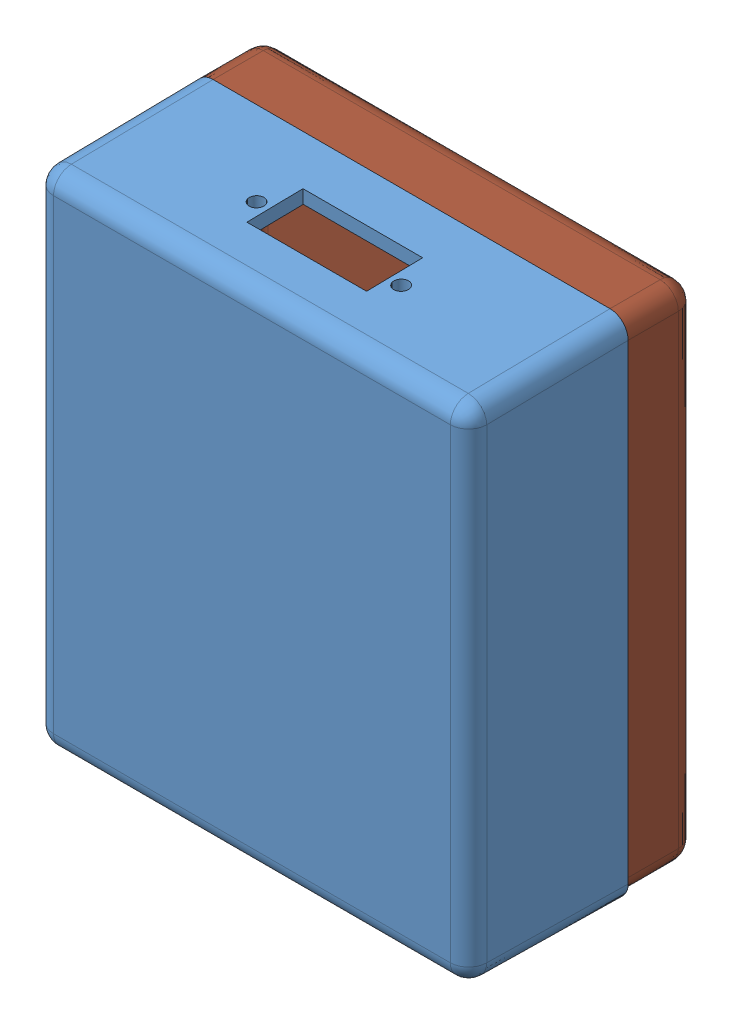
SolidWorks assembly Assem1, configuration Default. Lengths in mm.
Overall size (95 111.22 50).
418 component instances, 30 part files, 6 mates.
Components (placement in the parent):
- below part-1: below part [Default] at (-70.2324 -43.7689 -6.4145) size (95 111.22 37.01)
- Cell_module.step-1: Cell_module.step [Default] at (48.1396 -72.1244 16.2355) x (-1 0 0) z (0 0 -1) size (84.21 76.07 15.13)
  - Board.step-1: Board.step [Default] at origin size (82.17 76.07 0.41)
    - Open CASCADE STEP translator 6.8 1.1.1.step-1: Open CASCADE STEP translator 6.8 1.1.1.step [Default] at (0 0 -0.4115) size (82.17 76.07 0.41)
  - J3.step-1: J3.step [Default] at origin size (11.51 9.91 13)
    - 5828975392.step-1: 5828975392.step [Default] at (116.226 82.501 3.81) x (0 1 0) z (1 0 0) size (9.91 13 11.51)
  - J2.step-1: J2.step [Default] at origin size (11.51 9.91 13)
    - 5828975392.step-1: 5828975392.step [Default] at (116.226 112.989 3.81) x (0 1 0) z (1 0 0) size (9.91 13 11.51)
  - J1.step-1: J1.step [Default] at origin size (11.51 9.91 13)
    - 5828975392.step-1: 5828975392.step [Default] at (116.226 51.895 3.81) x (0 1 0) z (1 0 0) size (9.91 13 11.51)
  - Thermal.step-1: Thermal.step [Default] at origin size (12.18 15.85 12.05)
    - 5828975232.step-1: 5828975232.step [Default] at (118.372 66.6952 0.49) x (0 1 0) z (1 0 0) size (15.85 12.05 12.18)
      - Open CASCADE STEP translator 6.8 1.5.1.1.step-1: Open CASCADE STEP translator 6.8 1.5.1.1.step [Default] at origin size (15.85 12.05 12.18)
      - Open CASCADE STEP translator 6.8 1.5.1.2.step-1: Open CASCADE STEP translator 6.8 1.5.1.2.step [Default] at origin
  - Power.step-1: Power.step [Default] at origin size (12.18 15.85 12.05)
    - 5828975232.step-1: 5828975232.step [Default] at (118.372 97.1832 0.49) x (0 1 0) z (1 0 0) size (15.85 12.05 12.18)
      - Open CASCADE STEP translator 6.8 1.5.1.1.step-1: Open CASCADE STEP translator 6.8 1.5.1.1.step [Default] at origin size (15.85 12.05 12.18)
      - Open CASCADE STEP translator 6.8 1.5.1.2.step-1: Open CASCADE STEP translator 6.8 1.5.1.2.step [Default] at origin
  - U1_U5.step-1: U1_U5.step [Default] at origin size (7 2.7 2)
    - 5828972992.step-1: 5828972992.step [Default] at (52.631 109.3475 0) x (1 0 0) z (0 0 1) size (7 2.7 2)
      - Body.step-1: Body.step [Default] at origin size (4.4 2.7 1.95)
      - PinsArrayLR.step-1: PinsArrayLR.step [Default] at origin size (7 1.67 1.12)
  - U1_U4.step-1: U1_U4.step [Default] at origin size (7 2.7 2)
    - 5828972992.step-1: 5828972992.step [Default] at (52.631 96.9015 0) x (1 0 0) z (0 0 1) size (7 2.7 2)
      - Body.step-1: Body.step [Default] at origin size (4.4 2.7 1.95)
      - PinsArrayLR.step-1: PinsArrayLR.step [Default] at origin size (7 1.67 1.12)
  - U1_U3.step-1: U1_U3.step [Default] at origin size (7 2.7 2)
    - 5828972992.step-1: 5828972992.step [Default] at (52.631 85.0905 0) x (1 0 0) z (0 0 1) size (7 2.7 2)
      - Body.step-1: Body.step [Default] at origin size (4.4 2.7 1.95)
      - PinsArrayLR.step-1: PinsArrayLR.step [Default] at origin size (7 1.67 1.12)
  - U1_U2.step-1: U1_U2.step [Default] at origin size (7 2.7 2)
    - 5828972992.step-1: 5828972992.step [Default] at (52.631 72.9055 0) x (1 0 0) z (0 0 1) size (7 2.7 2)
      - Body.step-1: Body.step [Default] at origin size (4.4 2.7 1.95)
      - PinsArrayLR.step-1: PinsArrayLR.step [Default] at origin size (7 1.67 1.12)
  - U1_U1.step-1: U1_U1.step [Default] at origin size (7 2.7 2)
    - 5828972992.step-1: 5828972992.step [Default] at (52.631 61.3884 0) x (1 0 0) z (0 0 1) size (7 2.7 2)
      - Body.step-1: Body.step [Default] at origin size (4.4 2.7 1.95)
      - PinsArrayLR.step-1: PinsArrayLR.step [Default] at origin size (7 1.67 1.12)
  - Tx.step-1: Tx.step [Default] at origin size (7.4 5.75 10.4)
    - 5828979312.step-1: 5828979312.step [Default] at (74.1355 115.951 0) x (-1 0 0) z (0 1 0) size (7.4 10.4 5.75)
  - Rx.step-1: Rx.step [Default] at origin size (7.4 5.75 10.4)
    - 5828972752.step-1: 5828972752.step [Default] at (73.259 48.658 0) x (1 0 0) z (0 -1 0) size (7.4 10.4 5.75)
  - R28_U5.step-1: R28_U5.step [Default] at origin size (5 2.55 1.07)
    - Res_Yageo_RC2010JK-071KL_eec.step-1: Res_Yageo_RC2010JK-071KL_eec.step [Default] at (82.99 109.347 0) x (-1 0 0) z (0 0 1) size (5 2.55 1.07)
      - RC2010JK-071KL.step-1: RC2010JK-071KL.step [Default] x (1 0 0) z (0 -1 0) size (5 0.65 2.5)
      - Yageo.step-1: Yageo.step [Default] at (0.1744 -0.7742 0.648) size (1.81 0.83 0.83)
  - R28_U4.step-1: R28_U4.step [Default] at origin size (5 2.55 1.07)
    - Res_Yageo_RC2010JK-071KL_eec.step-1: Res_Yageo_RC2010JK-071KL_eec.step [Default] at (82.99 95.504 0) x (-1 0 0) z (0 0 1) size (5 2.55 1.07)
      - RC2010JK-071KL.step-1: RC2010JK-071KL.step [Default] x (1 0 0) z (0 -1 0) size (5 0.65 2.5)
      - Yageo.step-1: Yageo.step [Default] at (0.1744 -0.7742 0.648) size (1.81 0.83 0.83)
  - R28_U3.step-1: R28_U3.step [Default] at origin size (5 2.55 1.07)
    - Res_Yageo_RC2010JK-071KL_eec.step-1: Res_Yageo_RC2010JK-071KL_eec.step [Default] at (82.99 80.391 0) x (-1 0 0) z (0 0 1) size (5 2.55 1.07)
      - RC2010JK-071KL.step-1: RC2010JK-071KL.step [Default] x (1 0 0) z (0 -1 0) size (5 0.65 2.5)
      - Yageo.step-1: Yageo.step [Default] at (0.1744 -0.7742 0.648) size (1.81 0.83 0.83)
  - R28_U2.step-1: R28_U2.step [Default] at origin size (5 2.55 1.07)
    - Res_Yageo_RC2010JK-071KL_eec.step-1: Res_Yageo_RC2010JK-071KL_eec.step [Default] at (82.99 64.643 0) x (-1 0 0) z (0 0 1) size (5 2.55 1.07)
      - RC2010JK-071KL.step-1: RC2010JK-071KL.step [Default] x (1 0 0) z (0 -1 0) size (5 0.65 2.5)
      - Yageo.step-1: Yageo.step [Default] at (0.1744 -0.7742 0.648) size (1.81 0.83 0.83)
  - R28_U1.step-1: R28_U1.step [Default] at origin size (5 2.55 1.07)
    - Res_Yageo_RC2010JK-071KL_eec.step-1: Res_Yageo_RC2010JK-071KL_eec.step [Default] at (82.99 49.911 0) x (-1 0 0) z (0 0 1) size (5 2.55 1.07)
      - RC2010JK-071KL.step-1: RC2010JK-071KL.step [Default] x (1 0 0) z (0 -1 0) size (5 0.65 2.5)
      - Yageo.step-1: Yageo.step [Default] at (0.1744 -0.7742 0.648) size (1.81 0.83 0.83)
  - R27_U5.step-1: R27_U5.step [Default] at origin size (5 2.55 1.07)
    - Res_Yageo_RC2010JK-071KL_eec.step-1: Res_Yageo_RC2010JK-071KL_eec.step [Default] at (89.535 106.4728 0) x (-1 0 0) z (0 0 1) size (5 2.55 1.07)
      - RC2010JK-071KL.step-1: RC2010JK-071KL.step [Default] x (1 0 0) z (0 -1 0) size (5 0.65 2.5)
      - Yageo.step-1: Yageo.step [Default] at (0.1744 -0.7742 0.648) size (1.81 0.83 0.83)
  - R27_U4.step-1: R27_U4.step [Default] at origin size (5 2.55 1.07)
    - Res_Yageo_RC2010JK-071KL_eec.step-1: Res_Yageo_RC2010JK-071KL_eec.step [Default] at (89.535 92.1418 0) x (-1 0 0) z (0 0 1) size (5 2.55 1.07)
      - RC2010JK-071KL.step-1: RC2010JK-071KL.step [Default] x (1 0 0) z (0 -1 0) size (5 0.65 2.5)
      - Yageo.step-1: Yageo.step [Default] at (0.1744 -0.7742 0.648) size (1.81 0.83 0.83)
  - R27_U3.step-1: R27_U3.step [Default] at origin size (5 2.55 1.07)
    - Res_Yageo_RC2010JK-071KL_eec.step-1: Res_Yageo_RC2010JK-071KL_eec.step [Default] at (89.535 77.8109 0) x (-1 0 0) z (0 0 1) size (5 2.55 1.07)
      - RC2010JK-071KL.step-1: RC2010JK-071KL.step [Default] x (1 0 0) z (0 -1 0) size (5 0.65 2.5)
      - Yageo.step-1: Yageo.step [Default] at (0.1744 -0.7742 0.648) size (1.81 0.83 0.83)
  - R27_U2.step-1: R27_U2.step [Default] at origin size (5 2.55 1.07)
    - Res_Yageo_RC2010JK-071KL_eec.step-1: Res_Yageo_RC2010JK-071KL_eec.step [Default] at (89.535 63.4799 0) x (-1 0 0) z (0 0 1) size (5 2.55 1.07)
      - RC2010JK-071KL.step-1: RC2010JK-071KL.step [Default] x (1 0 0) z (0 -1 0) size (5 0.65 2.5)
      - Yageo.step-1: Yageo.step [Default] at (0.1744 -0.7742 0.648) size (1.81 0.83 0.83)
  - R27_U1.step-1: R27_U1.step [Default] at origin size (5 2.55 1.07)
    - Res_Yageo_RC2010JK-071KL_eec.step-1: Res_Yageo_RC2010JK-071KL_eec.step [Default] at (89.535 49.149 0) x (-1 0 0) z (0 0 1) size (5 2.55 1.07)
      - RC2010JK-071KL.step-1: RC2010JK-071KL.step [Default] x (1 0 0) z (0 -1 0) size (5 0.65 2.5)
      - Yageo.step-1: Yageo.step [Default] at (0.1744 -0.7742 0.648) size (1.81 0.83 0.83)
  - R26_U5.step-1: R26_U5.step [Default] at origin size (5 2.55 1.07)
    - Res_Yageo_RC2010JK-071KL_eec.step-1: Res_Yageo_RC2010JK-071KL_eec.step [Default] at (82.99 113.03 0) size (5 2.55 1.07)
      - RC2010JK-071KL.step-1: RC2010JK-071KL.step [Default] x (1 0 0) z (0 -1 0) size (5 0.65 2.5)
      - Yageo.step-1: Yageo.step [Default] at (0.1744 -0.7742 0.648) size (1.81 0.83 0.83)
  - R26_U4.step-1: R26_U4.step [Default] at origin size (5 2.55 1.07)
    - Res_Yageo_RC2010JK-071KL_eec.step-1: Res_Yageo_RC2010JK-071KL_eec.step [Default] at (82.99 99.5045 0) size (5 2.55 1.07)
      - RC2010JK-071KL.step-1: RC2010JK-071KL.step [Default] x (1 0 0) z (0 -1 0) size (5 0.65 2.5)
      - Yageo.step-1: Yageo.step [Default] at (0.1744 -0.7742 0.648) size (1.81 0.83 0.83)
  - R26_U3.step-1: R26_U3.step [Default] at origin size (5 2.55 1.07)
    - Res_Yageo_RC2010JK-071KL_eec.step-1: Res_Yageo_RC2010JK-071KL_eec.step [Default] at (82.99 84.582 0) size (5 2.55 1.07)
      - RC2010JK-071KL.step-1: RC2010JK-071KL.step [Default] x (1 0 0) z (0 -1 0) size (5 0.65 2.5)
      - Yageo.step-1: Yageo.step [Default] at (0.1744 -0.7742 0.648) size (1.81 0.83 0.83)
  - R26_U2.step-1: R26_U2.step [Default] at origin size (5 2.55 1.07)
    - Res_Yageo_RC2010JK-071KL_eec.step-1: Res_Yageo_RC2010JK-071KL_eec.step [Default] at (82.99 68.961 0) size (5 2.55 1.07)
      - RC2010JK-071KL.step-1: RC2010JK-071KL.step [Default] x (1 0 0) z (0 -1 0) size (5 0.65 2.5)
      - Yageo.step-1: Yageo.step [Default] at (0.1744 -0.7742 0.648) size (1.81 0.83 0.83)
  - R26_U1.step-1: R26_U1.step [Default] at origin size (5 2.55 1.07)
    - Res_Yageo_RC2010JK-071KL_eec.step-1: Res_Yageo_RC2010JK-071KL_eec.step [Default] at (83.058 54.102 0) size (5 2.55 1.07)
      - RC2010JK-071KL.step-1: RC2010JK-071KL.step [Default] x (1 0 0) z (0 -1 0) size (5 0.65 2.5)
      - Yageo.step-1: Yageo.step [Default] at (0.1744 -0.7742 0.648) size (1.81 0.83 0.83)
  - R25_U5.step-1: R25_U5.step [Default] at origin size (5 2.55 1.07)
    - Res_Yageo_RC2010JK-071KL_eec.step-1: Res_Yageo_RC2010JK-071KL_eec.step [Default] at (89.535 110.0555 0) size (5 2.55 1.07)
      - RC2010JK-071KL.step-1: RC2010JK-071KL.step [Default] x (1 0 0) z (0 -1 0) size (5 0.65 2.5)
      - Yageo.step-1: Yageo.step [Default] at (0.1744 -0.7742 0.648) size (1.81 0.83 0.83)
  - R25_U4.step-1: R25_U4.step [Default] at origin size (5 2.55 1.07)
    - Res_Yageo_RC2010JK-071KL_eec.step-1: Res_Yageo_RC2010JK-071KL_eec.step [Default] at (89.535 95.7246 0) size (5 2.55 1.07)
      - RC2010JK-071KL.step-1: RC2010JK-071KL.step [Default] x (1 0 0) z (0 -1 0) size (5 0.65 2.5)
      - Yageo.step-1: Yageo.step [Default] at (0.1744 -0.7742 0.648) size (1.81 0.83 0.83)
  - R25_U3.step-1: R25_U3.step [Default] at origin size (5 2.55 1.07)
    - Res_Yageo_RC2010JK-071KL_eec.step-1: Res_Yageo_RC2010JK-071KL_eec.step [Default] at (89.535 81.3936 0) size (5 2.55 1.07)
      - RC2010JK-071KL.step-1: RC2010JK-071KL.step [Default] x (1 0 0) z (0 -1 0) size (5 0.65 2.5)
      - Yageo.step-1: Yageo.step [Default] at (0.1744 -0.7742 0.648) size (1.81 0.83 0.83)
  - R25_U2.step-1: R25_U2.step [Default] at origin size (5 2.55 1.07)
    - Res_Yageo_RC2010JK-071KL_eec.step-1: Res_Yageo_RC2010JK-071KL_eec.step [Default] at (89.535 67.0627 0) size (5 2.55 1.07)
      - RC2010JK-071KL.step-1: RC2010JK-071KL.step [Default] x (1 0 0) z (0 -1 0) size (5 0.65 2.5)
      - Yageo.step-1: Yageo.step [Default] at (0.1744 -0.7742 0.648) size (1.81 0.83 0.83)
  - R25_U1.step-1: R25_U1.step [Default] at origin size (5 2.55 1.07)
    - Res_Yageo_RC2010JK-071KL_eec.step-1: Res_Yageo_RC2010JK-071KL_eec.step [Default] at (89.535 52.7317 0) size (5 2.55 1.07)
      - RC2010JK-071KL.step-1: RC2010JK-071KL.step [Default] x (1 0 0) z (0 -1 0) size (5 0.65 2.5)
      - Yageo.step-1: Yageo.step [Default] at (0.1744 -0.7742 0.648) size (1.81 0.83 0.83)
  - R24_U5.step-1: R24_U5.step [Default] at origin size (5 2.55 1.07)
    - Res_Yageo_RC2010JK-071KL_eec.step-1: Res_Yageo_RC2010JK-071KL_eec.step [Default] at (82.99 116.713 0) x (-1 0 0) z (0 0 1) size (5 2.55 1.07)
      - RC2010JK-071KL.step-1: RC2010JK-071KL.step [Default] x (1 0 0) z (0 -1 0) size (5 0.65 2.5)
      - Yageo.step-1: Yageo.step [Default] at (0.1744 -0.7742 0.648) size (1.81 0.83 0.83)
  - R24_U4.step-1: R24_U4.step [Default] at origin size (5 2.55 1.07)
    - Res_Yageo_RC2010JK-071KL_eec.step-1: Res_Yageo_RC2010JK-071KL_eec.step [Default] at (82.99 103.505 0) x (-1 0 0) z (0 0 1) size (5 2.55 1.07)
      - RC2010JK-071KL.step-1: RC2010JK-071KL.step [Default] x (1 0 0) z (0 -1 0) size (5 0.65 2.5)
      - Yageo.step-1: Yageo.step [Default] at (0.1744 -0.7742 0.648) size (1.81 0.83 0.83)
  - R24_U3.step-1: R24_U3.step [Default] at origin size (5 2.55 1.07)
    - Res_Yageo_RC2010JK-071KL_eec.step-1: Res_Yageo_RC2010JK-071KL_eec.step [Default] at (82.99 88.773 0) x (-1 0 0) z (0 0 1) size (5 2.55 1.07)
      - RC2010JK-071KL.step-1: RC2010JK-071KL.step [Default] x (1 0 0) z (0 -1 0) size (5 0.65 2.5)
      - Yageo.step-1: Yageo.step [Default] at (0.1744 -0.7742 0.648) size (1.81 0.83 0.83)
  - R24_U2.step-1: R24_U2.step [Default] at origin size (5 2.55 1.07)
    - Res_Yageo_RC2010JK-071KL_eec.step-1: Res_Yageo_RC2010JK-071KL_eec.step [Default] at (82.99 73.279 0) x (-1 0 0) z (0 0 1) size (5 2.55 1.07)
      - RC2010JK-071KL.step-1: RC2010JK-071KL.step [Default] x (1 0 0) z (0 -1 0) size (5 0.65 2.5)
      - Yageo.step-1: Yageo.step [Default] at (0.1744 -0.7742 0.648) size (1.81 0.83 0.83)
  - R24_U1.step-1: R24_U1.step [Default] at origin size (5 2.55 1.07)
    - Res_Yageo_RC2010JK-071KL_eec.step-1: Res_Yageo_RC2010JK-071KL_eec.step [Default] at (82.99 58.547 0) x (-1 0 0) z (0 0 1) size (5 2.55 1.07)
      - RC2010JK-071KL.step-1: RC2010JK-071KL.step [Default] x (1 0 0) z (0 -1 0) size (5 0.65 2.5)
      - Yageo.step-1: Yageo.step [Default] at (0.1744 -0.7742 0.648) size (1.81 0.83 0.83)
  - R22_U5.step-1: R22_U5.step [Default] at origin size (5 2.55 1.07)
    - Res_Yageo_RC2010JK-071KL_eec.step-1: Res_Yageo_RC2010JK-071KL_eec.step [Default] at (89.535 117.221 0) x (-1 0 0) z (0 0 1) size (5 2.55 1.07)
      - RC2010JK-071KL.step-1: RC2010JK-071KL.step [Default] x (1 0 0) z (0 -1 0) size (5 0.65 2.5)
      - Yageo.step-1: Yageo.step [Default] at (0.1744 -0.7742 0.648) size (1.81 0.83 0.83)
  - R22_U4.step-1: R22_U4.step [Default] at origin size (5 2.55 1.07)
    - Res_Yageo_RC2010JK-071KL_eec.step-1: Res_Yageo_RC2010JK-071KL_eec.step [Default] at (89.535 102.743 0) x (-1 0 0) z (0 0 1) size (5 2.55 1.07)
      - RC2010JK-071KL.step-1: RC2010JK-071KL.step [Default] x (1 0 0) z (0 -1 0) size (5 0.65 2.5)
      - Yageo.step-1: Yageo.step [Default] at (0.1744 -0.7742 0.648) size (1.81 0.83 0.83)
  - R22_U3.step-1: R22_U3.step [Default] at origin size (5 2.55 1.07)
    - Res_Yageo_RC2010JK-071KL_eec.step-1: Res_Yageo_RC2010JK-071KL_eec.step [Default] at (89.535 88.5591 0) x (-1 0 0) z (0 0 1) size (5 2.55 1.07)
      - RC2010JK-071KL.step-1: RC2010JK-071KL.step [Default] x (1 0 0) z (0 -1 0) size (5 0.65 2.5)
      - Yageo.step-1: Yageo.step [Default] at (0.1744 -0.7742 0.648) size (1.81 0.83 0.83)
  - R22_U2.step-1: R22_U2.step [Default] at origin size (5 2.55 1.07)
    - Res_Yageo_RC2010JK-071KL_eec.step-1: Res_Yageo_RC2010JK-071KL_eec.step [Default] at (89.535 74.2281 0) x (-1 0 0) z (0 0 1) size (5 2.55 1.07)
      - RC2010JK-071KL.step-1: RC2010JK-071KL.step [Default] x (1 0 0) z (0 -1 0) size (5 0.65 2.5)
      - Yageo.step-1: Yageo.step [Default] at (0.1744 -0.7742 0.648) size (1.81 0.83 0.83)
  - R22_U1.step-1: R22_U1.step [Default] at origin size (5 2.55 1.07)
    - Res_Yageo_RC2010JK-071KL_eec.step-1: Res_Yageo_RC2010JK-071KL_eec.step [Default] at (89.535 59.8972 0) x (-1 0 0) z (0 0 1) size (5 2.55 1.07)
      - RC2010JK-071KL.step-1: RC2010JK-071KL.step [Default] x (1 0 0) z (0 -1 0) size (5 0.65 2.5)
      - Yageo.step-1: Yageo.step [Default] at (0.1744 -0.7742 0.648) size (1.81 0.83 0.83)
  - R19_U5.step-1: R19_U5.step [Default] at origin size (4.4 2.7 2.01)
    - 5828980992.step-1: 5828980992.step [Default] at (89.408 113.538 0) x (-1 0 0) z (0 0 1) size (4.4 2.7 2.01)
      - term1.step-1: term1.step [Default] at (-1 -0.625 0) size (0.2 1.25 0.95)
      - term2.step-1: term2.step [Default] at (0.8 -0.625 0) size (0.2 1.25 0.95)
      - Body.step-1: Body.step [Default] at (-0.8 -0.6125 0.0095) size (4.4 2.7 1.95)
  - R19_U4.step-1: R19_U4.step [Default] at origin size (4.4 2.7 2.01)
    - 5828980992.step-1: 5828980992.step [Default] at (89.408 99.187 0) x (-1 0 0) z (0 0 1) size (4.4 2.7 2.01)
      - term1.step-1: term1.step [Default] at (-1 -0.625 0) size (0.2 1.25 0.95)
      - term2.step-1: term2.step [Default] at (0.8 -0.625 0) size (0.2 1.25 0.95)
      - Body.step-1: Body.step [Default] at (-0.8 -0.6125 0.0095) size (4.4 2.7 1.95)
  - R19_U3.step-1: R19_U3.step [Default] at origin size (4.4 2.7 2.01)
    - 5828980992.step-1: 5828980992.step [Default] at (89.408 84.836 0) x (-1 0 0) z (0 0 1) size (4.4 2.7 2.01)
      - term1.step-1: term1.step [Default] at (-1 -0.625 0) size (0.2 1.25 0.95)
      - term2.step-1: term2.step [Default] at (0.8 -0.625 0) size (0.2 1.25 0.95)
      - Body.step-1: Body.step [Default] at (-0.8 -0.6125 0.0095) size (4.4 2.7 1.95)
  - R19_U2.step-1: R19_U2.step [Default] at origin size (4.4 2.7 2.01)
    - 5828980992.step-1: 5828980992.step [Default] at (89.408 70.485 0) x (-1 0 0) z (0 0 1) size (4.4 2.7 2.01)
      - term1.step-1: term1.step [Default] at (-1 -0.625 0) size (0.2 1.25 0.95)
      - term2.step-1: term2.step [Default] at (0.8 -0.625 0) size (0.2 1.25 0.95)
      - Body.step-1: Body.step [Default] at (-0.8 -0.6125 0.0095) size (4.4 2.7 1.95)
  - R19_U1.step-1: R19_U1.step [Default] at origin size (4.4 2.7 2.01)
    - 5828980992.step-1: 5828980992.step [Default] at (89.408 56.134 0) x (-1 0 0) z (0 0 1) size (4.4 2.7 2.01)
      - term1.step-1: term1.step [Default] at (-1 -0.625 0) size (0.2 1.25 0.95)
      - term2.step-1: term2.step [Default] at (0.8 -0.625 0) size (0.2 1.25 0.95)
      - Body.step-1: Body.step [Default] at (-0.8 -0.6125 0.0095) size (4.4 2.7 1.95)
  - R18_U5.step-1: R18_U5.step [Default] at origin size (2 1.28 0.65)
    - 5828976432.step-1: 5828976432.step [Default] at (46.1639 106.6602 0) x (-1 0 0) z (0 0 1) size (2 1.28 0.65)
      - term1-0.step-1: term1-0.step [Default] at (-1 -0.6375 0) size (0.4 1.28 0.65)
      - term2-1.step-1: term2-1.step [Default] at (0.6 -0.6375 0) size (0.4 1.28 0.65)
      - body-2.step-1: body-2.step [Default] at (-0.6 -0.6248 0.0065) size (1.2 1.25 0.64)
  - R18_U4.step-1: R18_U4.step [Default] at origin size (2 1.28 0.65)
    - 5828976432.step-1: 5828976432.step [Default] at (46.1639 94.2777 0) x (-1 0 0) z (0 0 1) size (2 1.28 0.65)
      - term1-0.step-1: term1-0.step [Default] at (-1 -0.6375 0) size (0.4 1.28 0.65)
      - term2-1.step-1: term2-1.step [Default] at (0.6 -0.6375 0) size (0.4 1.28 0.65)
      - body-2.step-1: body-2.step [Default] at (-0.6 -0.6248 0.0065) size (1.2 1.25 0.64)
  - R18_U3.step-1: R18_U3.step [Default] at origin size (2 1.28 0.65)
    - 5828976432.step-1: 5828976432.step [Default] at (46.101 82.296 0) x (-1 0 0) z (0 0 1) size (2 1.28 0.65)
      - term1-0.step-1: term1-0.step [Default] at (-1 -0.6375 0) size (0.4 1.28 0.65)
      - term2-1.step-1: term2-1.step [Default] at (0.6 -0.6375 0) size (0.4 1.28 0.65)
      - body-2.step-1: body-2.step [Default] at (-0.6 -0.6248 0.0065) size (1.2 1.25 0.64)
  - R18_U2.step-1: R18_U2.step [Default] at origin size (2 1.28 0.65)
    - 5828976432.step-1: 5828976432.step [Default] at (46.101 70.485 0) x (-1 0 0) z (0 0 1) size (2 1.28 0.65)
      - term1-0.step-1: term1-0.step [Default] at (-1 -0.6375 0) size (0.4 1.28 0.65)
      - term2-1.step-1: term2-1.step [Default] at (0.6 -0.6375 0) size (0.4 1.28 0.65)
      - body-2.step-1: body-2.step [Default] at (-0.6 -0.6248 0.0065) size (1.2 1.25 0.64)
  - R18_U1.step-1: R18_U1.step [Default] at origin size (2 1.28 0.65)
    - 5828976432.step-1: 5828976432.step [Default] at (46.202 58.42 0) x (-1 0 0) z (0 0 1) size (2 1.28 0.65)
      - term1-0.step-1: term1-0.step [Default] at (-1 -0.6375 0) size (0.4 1.28 0.65)
      - term2-1.step-1: term2-1.step [Default] at (0.6 -0.6375 0) size (0.4 1.28 0.65)
      - body-2.step-1: body-2.step [Default] at (-0.6 -0.6248 0.0065) size (1.2 1.25 0.64)
  - R17_U5.step-1: R17_U5.step [Default] at origin size (2 1.28 0.65)
    - 5828976432.step-1: 5828976432.step [Default] at (68.5048 105.029 0) x (-1 0 0) z (0 0 1) size (2 1.28 0.65)
      - term1-0.step-1: term1-0.step [Default] at (-1 -0.6375 0) size (0.4 1.28 0.65)
      - term2-1.step-1: term2-1.step [Default] at (0.6 -0.6375 0) size (0.4 1.28 0.65)
      - body-2.step-1: body-2.step [Default] at (-0.6 -0.6248 0.0065) size (1.2 1.25 0.64)
  - R17_U4.step-1: R17_U4.step [Default] at origin size (2 1.28 0.65)
    - 5828976432.step-1: 5828976432.step [Default] at (68.5048 92.456 0) x (-1 0 0) z (0 0 1) size (2 1.28 0.65)
      - term1-0.step-1: term1-0.step [Default] at (-1 -0.6375 0) size (0.4 1.28 0.65)
      - term2-1.step-1: term2-1.step [Default] at (0.6 -0.6375 0) size (0.4 1.28 0.65)
      - body-2.step-1: body-2.step [Default] at (-0.6 -0.6248 0.0065) size (1.2 1.25 0.64)
  - R17_U3.step-1: R17_U3.step [Default] at origin size (2 1.28 0.65)
    - 5828976432.step-1: 5828976432.step [Default] at (68.5048 80.518 0) x (-1 0 0) z (0 0 1) size (2 1.28 0.65)
      - term1-0.step-1: term1-0.step [Default] at (-1 -0.6375 0) size (0.4 1.28 0.65)
      - term2-1.step-1: term2-1.step [Default] at (0.6 -0.6375 0) size (0.4 1.28 0.65)
      - body-2.step-1: body-2.step [Default] at (-0.6 -0.6248 0.0065) size (1.2 1.25 0.64)
  - R17_U2.step-1: R17_U2.step [Default] at origin size (2 1.28 0.65)
    - 5828976432.step-1: 5828976432.step [Default] at (68.5048 68.707 0) x (-1 0 0) z (0 0 1) size (2 1.28 0.65)
      - term1-0.step-1: term1-0.step [Default] at (-1 -0.6375 0) size (0.4 1.28 0.65)
      - term2-1.step-1: term2-1.step [Default] at (0.6 -0.6375 0) size (0.4 1.28 0.65)
      - body-2.step-1: body-2.step [Default] at (-0.6 -0.6248 0.0065) size (1.2 1.25 0.64)
  - R17_U1.step-1: R17_U1.step [Default] at origin size (2 1.28 0.65)
    - 5828976432.step-1: 5828976432.step [Default] at (68.5048 57.023 0) x (-1 0 0) z (0 0 1) size (2 1.28 0.65)
      - term1-0.step-1: term1-0.step [Default] at (-1 -0.6375 0) size (0.4 1.28 0.65)
      - term2-1.step-1: term2-1.step [Default] at (0.6 -0.6375 0) size (0.4 1.28 0.65)
      - body-2.step-1: body-2.step [Default] at (-0.6 -0.6248 0.0065) size (1.2 1.25 0.64)
  - R16_U5.step-1: R16_U5.step [Default] at origin size (2 1.28 0.65)
    - 5828979792.step-1: 5828979792.step [Default] at (41.4449 104.4568 0) x (1 0 0) z (0 0 1) size (2 1.28 0.65)
      - term1-3.step-1: term1-3.step [Default] at (-1 -0.6375 0) size (0.4 1.28 0.65)
      - term2-4.step-1: term2-4.step [Default] at (0.6 -0.6375 0) size (0.4 1.28 0.65)
      - body-5.step-1: body-5.step [Default] at (-0.6 -0.6248 0.0065) size (1.2 1.25 0.64)
  - R16_U4.step-1: R16_U4.step [Default] at origin size (2 1.28 0.65)
    - 5828979792.step-1: 5828979792.step [Default] at (41.4449 92.0955 0) x (1 0 0) z (0 0 1) size (2 1.28 0.65)
      - term1-3.step-1: term1-3.step [Default] at (-1 -0.6375 0) size (0.4 1.28 0.65)
      - term2-4.step-1: term2-4.step [Default] at (0.6 -0.6375 0) size (0.4 1.28 0.65)
      - body-5.step-1: body-5.step [Default] at (-0.6 -0.6248 0.0065) size (1.2 1.25 0.64)
  - R16_U3.step-1: R16_U3.step [Default] at origin size (2 1.28 0.65)
    - 5828979792.step-1: 5828979792.step [Default] at (41.4449 79.9458 0) x (1 0 0) z (0 0 1) size (2 1.28 0.65)
      - term1-3.step-1: term1-3.step [Default] at (-1 -0.6375 0) size (0.4 1.28 0.65)
      - term2-4.step-1: term2-4.step [Default] at (0.6 -0.6375 0) size (0.4 1.28 0.65)
      - body-5.step-1: body-5.step [Default] at (-0.6 -0.6248 0.0065) size (1.2 1.25 0.64)
  - R16_U2.step-1: R16_U2.step [Default] at origin size (2 1.28 0.65)
    - 5828979792.step-1: 5828979792.step [Default] at (41.4449 67.9255 0) x (1 0 0) z (0 0 1) size (2 1.28 0.65)
      - term1-3.step-1: term1-3.step [Default] at (-1 -0.6375 0) size (0.4 1.28 0.65)
      - term2-4.step-1: term2-4.step [Default] at (0.6 -0.6375 0) size (0.4 1.28 0.65)
      - body-5.step-1: body-5.step [Default] at (-0.6 -0.6248 0.0065) size (1.2 1.25 0.64)
  - R16_U1.step-1: R16_U1.step [Default] at origin size (2 1.28 0.65)
    - 5828979792.step-1: 5828979792.step [Default] at (41.4449 56.0432 0) x (1 0 0) z (0 0 1) size (2 1.28 0.65)
      - term1-3.step-1: term1-3.step [Default] at (-1 -0.6375 0) size (0.4 1.28 0.65)
      - term2-4.step-1: term2-4.step [Default] at (0.6 -0.6375 0) size (0.4 1.28 0.65)
      - body-5.step-1: body-5.step [Default] at (-0.6 -0.6248 0.0065) size (1.2 1.25 0.64)
  - R10_U5.step-1: R10_U5.step [Default] at origin size (5 2.55 1.07)
    - Res_Yageo_RC2010JK-071KL_eec.step-1: Res_Yageo_RC2010JK-071KL_eec.step [Default] at (96.012 109.347 0) x (-1 0 0) z (0 0 1) size (5 2.55 1.07)
      - RC2010JK-071KL.step-1: RC2010JK-071KL.step [Default] x (1 0 0) z (0 -1 0) size (5 0.65 2.5)
      - Yageo.step-1: Yageo.step [Default] at (0.1744 -0.7742 0.648) size (1.81 0.83 0.83)
  - R10_U4.step-1: R10_U4.step [Default] at origin size (5 2.55 1.07)
    - Res_Yageo_RC2010JK-071KL_eec.step-1: Res_Yageo_RC2010JK-071KL_eec.step [Default] at (96.012 95.504 0) x (-1 0 0) z (0 0 1) size (5 2.55 1.07)
      - RC2010JK-071KL.step-1: RC2010JK-071KL.step [Default] x (1 0 0) z (0 -1 0) size (5 0.65 2.5)
      - Yageo.step-1: Yageo.step [Default] at (0.1744 -0.7742 0.648) size (1.81 0.83 0.83)
  - R10_U3.step-1: R10_U3.step [Default] at origin size (5 2.55 1.07)
    - Res_Yageo_RC2010JK-071KL_eec.step-1: Res_Yageo_RC2010JK-071KL_eec.step [Default] at (96.012 80.391 0) x (-1 0 0) z (0 0 1) size (5 2.55 1.07)
      - RC2010JK-071KL.step-1: RC2010JK-071KL.step [Default] x (1 0 0) z (0 -1 0) size (5 0.65 2.5)
      - Yageo.step-1: Yageo.step [Default] at (0.1744 -0.7742 0.648) size (1.81 0.83 0.83)
  - R10_U2.step-1: R10_U2.step [Default] at origin size (5 2.55 1.07)
    - Res_Yageo_RC2010JK-071KL_eec.step-1: Res_Yageo_RC2010JK-071KL_eec.step [Default] at (96.012 64.643 0) x (-1 0 0) z (0 0 1) size (5 2.55 1.07)
      - RC2010JK-071KL.step-1: RC2010JK-071KL.step [Default] x (1 0 0) z (0 -1 0) size (5 0.65 2.5)
      - Yageo.step-1: Yageo.step [Default] at (0.1744 -0.7742 0.648) size (1.81 0.83 0.83)
  - R10_U1.step-1: R10_U1.step [Default] at origin size (5 2.55 1.07)
    - Res_Yageo_RC2010JK-071KL_eec.step-1: Res_Yageo_RC2010JK-071KL_eec.step [Default] at (96.012 49.911 0) x (-1 0 0) z (0 0 1) size (5 2.55 1.07)
      - RC2010JK-071KL.step-1: RC2010JK-071KL.step [Default] x (1 0 0) z (0 -1 0) size (5 0.65 2.5)
      - Yageo.step-1: Yageo.step [Default] at (0.1744 -0.7742 0.648) size (1.81 0.83 0.83)
  - R8_U5.step-1: R8_U5.step [Default] at origin size (5 2.55 1.07)
    - Res_Yageo_RC2010JK-071KL_eec.step-1: Res_Yageo_RC2010JK-071KL_eec.step [Default] at (96.012 113.03 0) size (5 2.55 1.07)
      - RC2010JK-071KL.step-1: RC2010JK-071KL.step [Default] x (1 0 0) z (0 -1 0) size (5 0.65 2.5)
      - Yageo.step-1: Yageo.step [Default] at (0.1744 -0.7742 0.648) size (1.81 0.83 0.83)
  - R8_U4.step-1: R8_U4.step [Default] at origin size (5 2.55 1.07)
    - Res_Yageo_RC2010JK-071KL_eec.step-1: Res_Yageo_RC2010JK-071KL_eec.step [Default] at (96.012 99.5045 0) size (5 2.55 1.07)
      - RC2010JK-071KL.step-1: RC2010JK-071KL.step [Default] x (1 0 0) z (0 -1 0) size (5 0.65 2.5)
      - Yageo.step-1: Yageo.step [Default] at (0.1744 -0.7742 0.648) size (1.81 0.83 0.83)
  - R8_U3.step-1: R8_U3.step [Default] at origin size (5 2.55 1.07)
    - Res_Yageo_RC2010JK-071KL_eec.step-1: Res_Yageo_RC2010JK-071KL_eec.step [Default] at (96.012 84.582 0) size (5 2.55 1.07)
      - RC2010JK-071KL.step-1: RC2010JK-071KL.step [Default] x (1 0 0) z (0 -1 0) size (5 0.65 2.5)
      - Yageo.step-1: Yageo.step [Default] at (0.1744 -0.7742 0.648) size (1.81 0.83 0.83)
  - R8_U2.step-1: R8_U2.step [Default] at origin size (5 2.55 1.07)
    - Res_Yageo_RC2010JK-071KL_eec.step-1: Res_Yageo_RC2010JK-071KL_eec.step [Default] at (96.012 68.961 0) size (5 2.55 1.07)
      - RC2010JK-071KL.step-1: RC2010JK-071KL.step [Default] x (1 0 0) z (0 -1 0) size (5 0.65 2.5)
      - Yageo.step-1: Yageo.step [Default] at (0.1744 -0.7742 0.648) size (1.81 0.83 0.83)
  - R8_U1.step-1: R8_U1.step [Default] at origin size (5 2.55 1.07)
    - Res_Yageo_RC2010JK-071KL_eec.step-1: Res_Yageo_RC2010JK-071KL_eec.step [Default] at (96.012 54.229 0) size (5 2.55 1.07)
      - RC2010JK-071KL.step-1: RC2010JK-071KL.step [Default] x (1 0 0) z (0 -1 0) size (5 0.65 2.5)
      - Yageo.step-1: Yageo.step [Default] at (0.1744 -0.7742 0.648) size (1.81 0.83 0.83)
  - R6_U5.step-1: R6_U5.step [Default] at origin size (5 2.55 1.07)
    - Res_Yageo_RC2010JK-071KL_eec.step-1: Res_Yageo_RC2010JK-071KL_eec.step [Default] at (96.012 116.713 0) size (5 2.55 1.07)
      - RC2010JK-071KL.step-1: RC2010JK-071KL.step [Default] x (1 0 0) z (0 -1 0) size (5 0.65 2.5)
      - Yageo.step-1: Yageo.step [Default] at (0.1744 -0.7742 0.648) size (1.81 0.83 0.83)
  - R6_U4.step-1: R6_U4.step [Default] at origin size (5 2.55 1.07)
    - Res_Yageo_RC2010JK-071KL_eec.step-1: Res_Yageo_RC2010JK-071KL_eec.step [Default] at (96.012 103.505 0) size (5 2.55 1.07)
      - RC2010JK-071KL.step-1: RC2010JK-071KL.step [Default] x (1 0 0) z (0 -1 0) size (5 0.65 2.5)
      - Yageo.step-1: Yageo.step [Default] at (0.1744 -0.7742 0.648) size (1.81 0.83 0.83)
  - R6_U3.step-1: R6_U3.step [Default] at origin size (5 2.55 1.07)
    - Res_Yageo_RC2010JK-071KL_eec.step-1: Res_Yageo_RC2010JK-071KL_eec.step [Default] at (96.012 88.773 0) size (5 2.55 1.07)
      - RC2010JK-071KL.step-1: RC2010JK-071KL.step [Default] x (1 0 0) z (0 -1 0) size (5 0.65 2.5)
      - Yageo.step-1: Yageo.step [Default] at (0.1744 -0.7742 0.648) size (1.81 0.83 0.83)
  - R6_U2.step-1: R6_U2.step [Default] at origin size (5 2.55 1.07)
    - Res_Yageo_RC2010JK-071KL_eec.step-1: Res_Yageo_RC2010JK-071KL_eec.step [Default] at (96.012 73.279 0) size (5 2.55 1.07)
      - RC2010JK-071KL.step-1: RC2010JK-071KL.step [Default] x (1 0 0) z (0 -1 0) size (5 0.65 2.5)
      - Yageo.step-1: Yageo.step [Default] at (0.1744 -0.7742 0.648) size (1.81 0.83 0.83)
  - R6_U1.step-1: R6_U1.step [Default] at origin size (5 2.55 1.07)
    - Res_Yageo_RC2010JK-071KL_eec.step-1: Res_Yageo_RC2010JK-071KL_eec.step [Default] at (96.012 58.547 0) size (5 2.55 1.07)
      - RC2010JK-071KL.step-1: RC2010JK-071KL.step [Default] x (1 0 0) z (0 -1 0) size (5 0.65 2.5)
      - Yageo.step-1: Yageo.step [Default] at (0.1744 -0.7742 0.648) size (1.81 0.83 0.83)
  - Q1_U5.step-1: Q1_U5.step [Default] at origin size (3.01 3.13 1.27)
    - 5828974272.step-1: 5828974272.step [Default] at (68.834 109.093 0) x (0 -1 0) z (0 0 1) size (3.13 3.01 1.27)
  - Q1_U4.step-1: Q1_U4.step [Default] at origin size (3.01 3.13 1.27)
    - 5828974272.step-1: 5828974272.step [Default] at (68.834 96.5989 0) x (0 -1 0) z (0 0 1) size (3.13 3.01 1.27)
  - Q1_U3.step-1: Q1_U3.step [Default] at origin size (3.01 3.13 1.27)
    - 5828974272.step-1: 5828974272.step [Default] at (68.834 84.7879 0) x (0 -1 0) z (0 0 1) size (3.13 3.01 1.27)
  - Q1_U2.step-1: Q1_U2.step [Default] at origin size (3.01 3.13 1.27)
    - 5828974272.step-1: 5828974272.step [Default] at (68.834 72.6029 0) x (0 -1 0) z (0 0 1) size (3.13 3.01 1.27)
  - Q1_U1.step-1: Q1_U1.step [Default] at origin size (3.01 3.13 1.27)
    - 5828974272.step-1: 5828974272.step [Default] at (68.834 61.0859 0) x (0 -1 0) z (0 0 1) size (3.13 3.01 1.27)
  - IC1_U5.step-1: IC1_U5.step [Default] at origin size (6 8.65 1.75)
    - 5828983152.step-1: 5828983152.step [Default] at (75.438 106.426 0) size (6 8.65 1.75)
      - Body-6.step-1: Body-6.step [Default] at origin size (3.9 8.65 1.57)
      - PinsArrayLR-7.step-1: PinsArrayLR-7.step [Default] at origin size (6 8.03 1)
  - IC1_U4.step-1: IC1_U4.step [Default] at origin size (6 8.65 1.75)
    - 5828983152.step-1: 5828983152.step [Default] at (75.438 94.3829 0) size (6 8.65 1.75)
      - Body-6.step-1: Body-6.step [Default] at origin size (3.9 8.65 1.57)
      - PinsArrayLR-7.step-1: PinsArrayLR-7.step [Default] at origin size (6 8.03 1)
  - IC1_U3.step-1: IC1_U3.step [Default] at origin size (6 8.65 1.75)
    - 5828983152.step-1: 5828983152.step [Default] at (75.438 82.3398 0) size (6 8.65 1.75)
      - Body-6.step-1: Body-6.step [Default] at origin size (3.9 8.65 1.57)
      - PinsArrayLR-7.step-1: PinsArrayLR-7.step [Default] at origin size (6 8.03 1)
  - IC1_U2.step-1: IC1_U2.step [Default] at origin size (6 8.65 1.75)
    - 5828983152.step-1: 5828983152.step [Default] at (75.438 70.2966 0) size (6 8.65 1.75)
      - Body-6.step-1: Body-6.step [Default] at origin size (3.9 8.65 1.57)
      - PinsArrayLR-7.step-1: PinsArrayLR-7.step [Default] at origin size (6 8.03 1)
  - IC1_U1.step-1: IC1_U1.step [Default] at origin size (6 8.65 1.75)
    - 5828983152.step-1: 5828983152.step [Default] at (75.438 58.2535 0) size (6 8.65 1.75)
      - Body-6.step-1: Body-6.step [Default] at origin size (3.9 8.65 1.57)
      - PinsArrayLR-7.step-1: PinsArrayLR-7.step [Default] at origin size (6 8.03 1)
  - F1_U5.step-1: F1_U5.step [Default] at origin size (3.24 4.55 0.85)
    - 5828974512.step-1: 5828974512.step [Default] at (59.309 108.063 0) x (0 1 0) z (0 0 1) size (4.55 3.24 0.85)
      - term1-8.step-1: term1-8.step [Default] at (-2.275 -1.62 0) size (0.3 3.24 0.85)
      - term2-9.step-1: term2-9.step [Default] at (1.975 -1.62 0) size (0.3 3.24 0.85)
      - body-10.step-1: body-10.step [Default] at (-1.975 -1.5876 0.0085) size (3.95 3.18 0.83)
  - F1_U4.step-1: F1_U4.step [Default] at origin size (3.24 4.55 0.85)
    - 5828974512.step-1: 5828974512.step [Default] at (59.309 95.5515 0) x (0 1 0) z (0 0 1) size (4.55 3.24 0.85)
      - term1-8.step-1: term1-8.step [Default] at (-2.275 -1.62 0) size (0.3 3.24 0.85)
      - term2-9.step-1: term2-9.step [Default] at (1.975 -1.62 0) size (0.3 3.24 0.85)
      - body-10.step-1: body-10.step [Default] at (-1.975 -1.5876 0.0085) size (3.95 3.18 0.83)
  - F1_U3.step-1: F1_U3.step [Default] at origin size (3.24 4.55 0.85)
    - 5828974512.step-1: 5828974512.step [Default] at (59.309 83.7405 0) x (0 1 0) z (0 0 1) size (4.55 3.24 0.85)
      - term1-8.step-1: term1-8.step [Default] at (-2.275 -1.62 0) size (0.3 3.24 0.85)
      - term2-9.step-1: term2-9.step [Default] at (1.975 -1.62 0) size (0.3 3.24 0.85)
      - body-10.step-1: body-10.step [Default] at (-1.975 -1.5876 0.0085) size (3.95 3.18 0.83)
  - F1_U2.step-1: F1_U2.step [Default] at origin size (3.24 4.55 0.85)
    - 5828974512.step-1: 5828974512.step [Default] at (59.309 71.5555 0) x (0 1 0) z (0 0 1) size (4.55 3.24 0.85)
      - term1-8.step-1: term1-8.step [Default] at (-2.275 -1.62 0) size (0.3 3.24 0.85)
      - term2-9.step-1: term2-9.step [Default] at (1.975 -1.62 0) size (0.3 3.24 0.85)
      - body-10.step-1: body-10.step [Default] at (-1.975 -1.5876 0.0085) size (3.95 3.18 0.83)
  - F1_U1.step-1: F1_U1.step [Default] at origin size (3.24 4.55 0.85)
    - 5828974512.step-1: 5828974512.step [Default] at (59.309 60.0385 0) x (0 1 0) z (0 0 1) size (4.55 3.24 0.85)
      - term1-8.step-1: term1-8.step [Default] at (-2.275 -1.62 0) size (0.3 3.24 0.85)
      - term2-9.step-1: term2-9.step [Default] at (1.975 -1.62 0) size (0.3 3.24 0.85)
      - body-10.step-1: body-10.step [Default] at (-1.975 -1.5876 0.0085) size (3.95 3.18 0.83)
  - D4_U5.step-1: D4_U5.step [Default] at origin size (1.64 0.8 0.42)
    - 5828982032.step-1: 5828982032.step [Default] at (45.9139 103.378 0) x (-1 0 0) z (0 0 1) size (1.64 0.8 0.42)
  - D4_U4.step-1: D4_U4.step [Default] at origin size (1.64 0.8 0.42)
    - 5828982032.step-1: 5828982032.step [Default] at (45.9139 91.059 0) x (-1 0 0) z (0 0 1) size (1.64 0.8 0.42)
  - D4_U3.step-1: D4_U3.step [Default] at origin size (1.64 0.8 0.42)
    - 5828982032.step-1: 5828982032.step [Default] at (45.9139 79.121 0) x (-1 0 0) z (0 0 1) size (1.64 0.8 0.42)
  - D4_U2.step-1: D4_U2.step [Default] at origin size (1.64 0.8 0.42)
    - 5828982032.step-1: 5828982032.step [Default] at (45.974 67.183 0) x (-1 0 0) z (0 0 1) size (1.64 0.8 0.42)
  - D4_U1.step-1: D4_U1.step [Default] at origin size (1.64 0.8 0.42)
    - 5828982032.step-1: 5828982032.step [Default] at (46.075 55.372 0) x (-1 0 0) z (0 0 1) size (1.64 0.8 0.42)
  - D3_U5.step-1: D3_U5.step [Default] at origin size (2 1.25 0.91)
    - 5828976752.step-1: 5828976752.step [Default] at (68.2548 101.854 0) x (-1 0 0) z (0 0 1) size (2 1.25 0.91)
      - Body-11.step-1: Body-11.step [Default] at (0 0 0.1) size (2 1.25 0.81)
      - Pins.step-1: Pins.step [Default] at origin size (1.88 1.08 0.1)
  - D3_U4.step-1: D3_U4.step [Default] at origin size (2 1.25 0.91)
    - 5828976752.step-1: 5828976752.step [Default] at (68.2548 89.408 0) x (-1 0 0) z (0 0 1) size (2 1.25 0.91)
      - Body-11.step-1: Body-11.step [Default] at (0 0 0.1) size (2 1.25 0.81)
      - Pins.step-1: Pins.step [Default] at origin size (1.88 1.08 0.1)
  - D3_U3.step-1: D3_U3.step [Default] at origin size (2 1.25 0.91)
    - 5828976752.step-1: 5828976752.step [Default] at (68.2548 77.343 0) x (-1 0 0) z (0 0 1) size (2 1.25 0.91)
      - Body-11.step-1: Body-11.step [Default] at (0 0 0.1) size (2 1.25 0.81)
      - Pins.step-1: Pins.step [Default] at origin size (1.88 1.08 0.1)
  - D3_U2.step-1: D3_U2.step [Default] at origin size (2 1.25 0.91)
    - 5828976752.step-1: 5828976752.step [Default] at (68.2548 65.532 0) x (-1 0 0) z (0 0 1) size (2 1.25 0.91)
      - Body-11.step-1: Body-11.step [Default] at (0 0 0.1) size (2 1.25 0.81)
      - Pins.step-1: Pins.step [Default] at origin size (1.88 1.08 0.1)
  - D3_U1.step-1: D3_U1.step [Default] at origin size (2 1.25 0.91)
    - 5828976752.step-1: 5828976752.step [Default] at (68.2548 53.975 0) x (-1 0 0) z (0 0 1) size (2 1.25 0.91)
      - Body-11.step-1: Body-11.step [Default] at (0 0 0.1) size (2 1.25 0.81)
      - Pins.step-1: Pins.step [Default] at origin size (1.88 1.08 0.1)
  - D2_U5.step-1: D2_U5.step [Default] at origin size (3.72 5.35 2.33)
    - 5828974992.step-1: 5828974992.step [Default] at (63.881 107.315 1.23) x (0 1 0) z (0 0 1) size (5.35 3.72 2.32)
  - D2_U4.step-1: D2_U4.step [Default] at origin size (3.72 5.35 2.33)
    - 5828974992.step-1: 5828974992.step [Default] at (63.881 94.9452 1.23) x (0 1 0) z (0 0 1) size (5.35 3.72 2.32)
  - D2_U3.step-1: D2_U3.step [Default] at origin size (3.72 5.35 2.33)
    - 5828974992.step-1: 5828974992.step [Default] at (63.881 83.312 1.23) x (0 1 0) z (0 0 1) size (5.35 3.72 2.32)
  - D2_U2.step-1: D2_U2.step [Default] at origin size (3.72 5.35 2.33)
    - 5828974992.step-1: 5828974992.step [Default] at (63.881 71.374 1.23) x (0 1 0) z (0 0 1) size (5.35 3.72 2.32)
  - D2_U1.step-1: D2_U1.step [Default] at origin size (3.72 5.35 2.33)
    - 5828974992.step-1: 5828974992.step [Default] at (63.881 59.69 1.23) x (0 1 0) z (0 0 1) size (5.35 3.72 2.32)
- Top Part-2: Top Part [Default] at (24.7676 66.842 -6.4145) x (0 0 -1) z (-1 0 0) size (16.25 110 95)
Mates (geometry in assembly coordinates):
- Coincident9: coincident anti-aligned: plane of below part-1 through (-70.2324 -6.4314 8.8855) normal (0 0 1); plane of Cell_module.step-1/Thermal.step-1/5828975232.step-1/Open CASCADE STEP translator 6.8 1.5.1.1.step-1 through (-70.2324 -13.3542 8.8855) normal (0 0 -1)
- Coincident10: coincident aligned: plane of below part-1 through (-70.2324 -43.7689 28.5855) normal (-1 0 0); plane of Cell_module.step-1/Thermal.step-1/5828975232.step-1/Open CASCADE STEP translator 6.8 1.5.1.1.step-1 through (-70.2324 -5.4292 15.7455) normal (-1 0 0)
- Coincident11: coincident anti-aligned: plane of below part-1 through (-70.2324 -13.3542 8.8855) normal (0 1 0); plane of Cell_module.step-1/Thermal.step-1/5828975232.step-1/Open CASCADE STEP translator 6.8 1.5.1.1.step-1 through (-70.2324 -13.3542 15.7455) normal (0 -1 0)
- Coincident12: coincident anti-aligned: line of below part-1 through (20.7676 66.842 -6.4145) axis (-1 0 0); line of Top Part-2 through (-66.2324 66.842 -6.4145) axis (1 0 0)
- Coincident14: coincident: plane of below part-1 through (-70.2324 -43.7689 28.5855) normal (-1 0 0); line of Top Part-2 through (-70.2324 -39.158 -6.4145) axis (0 1 0)
- Parallel1: parallel anti-aligned: line of below part-1 through (20.7676 -42.8444 -8.4145) axis (-1 0 0); line of Top Part-2 through (-66.2324 -43.158 -6.4145) axis (1 0 0)
